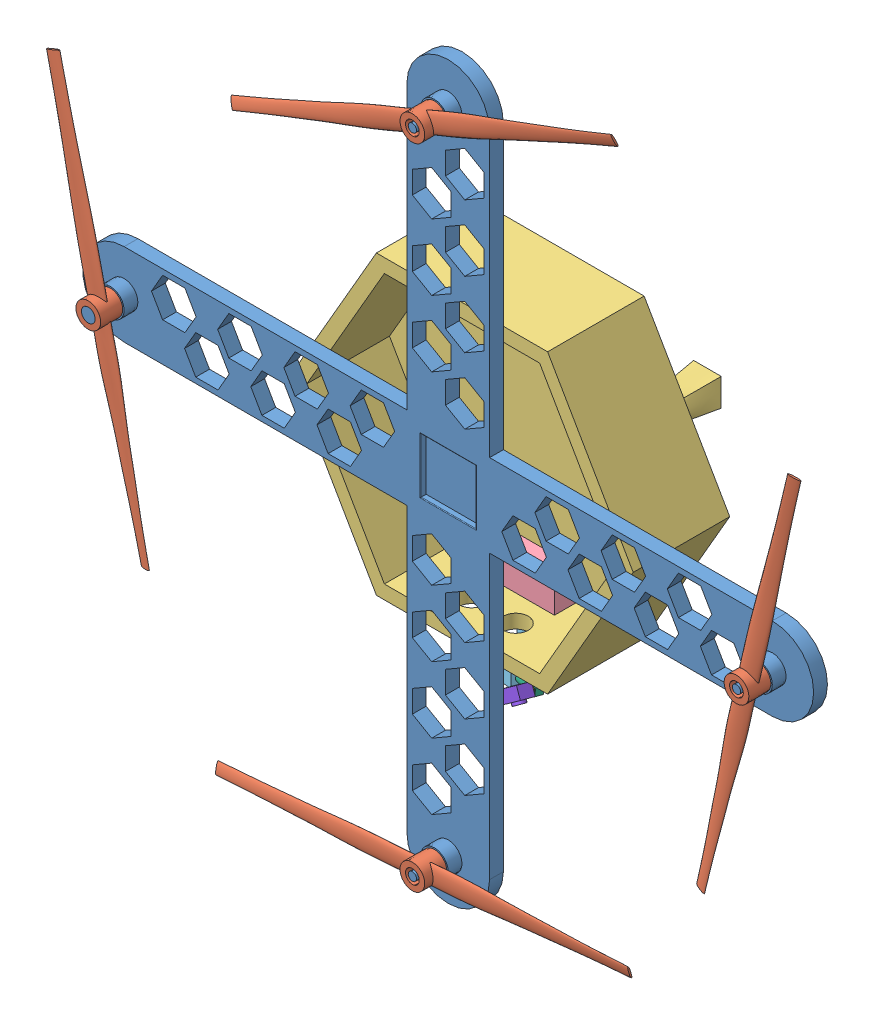
SolidWorks assembly Assembly1, configuration Default. Lengths in mm.
Overall size (277.47 282.88 68.01).
11 component instances, 8 part files, 24 mates.
Components (placement in the parent):
- arm-1: arm [Default] at (-17.0766 -45.3061 35) size (265 265 18)
- blade-1: blade [Default] at (-134.5766 -45.3061 53) x (0.974834 0.222931 0) z (0 0 -1) size (9 150.02 8)
- blade-2: blade [Default] at (-17.0766 72.1939 53) x (0.382949 -0.923769 0) z (0 0 -1) size (9 150.02 8)
- blade-3: blade [Default] at (100.4234 -45.3061 53) x (0.974033 -0.226406 0) z (0 0 -1) size (9 150.02 8)
- blade-4: blade [Default] at (-17.0766 -162.8061 45) x (-0.070402 0.997519 0) z (0 0 1) size (9 150.02 8)
- body-1: body [Default] at (-17.0766 -45.3061 35) x (1 0 0) z (0 0 -1) size (124.13 107.5 50.01)
- gimbal1-1: gimbal1 [Default] at (-17.0766 -84.0561 9.5) x (1 0 0) z (0 -1 0) size (25 9 20)
- gimbal2-1: gimbal2 [Default] at (-17.0766 -99.0561 9.5) x (-0.994374 0 -0.105926) z (0 -1 0) size (15.1 8.17 28)
- gimbal3-1: gimbal3 [Default] at (-22.0484 -124.5561 8.9704) x (-0.104139 0.182919 0.977597) z (0.994374 0 0.105926) size (4 3.01 8)
- gimbal4-1: gimbal4 [Default] at (-15.7412 -124.2817 11.1253) x (0.817116 0.5761 -0.020751) z (-0.104139 0.182919 0.977597) size (2.5 2.5 2.5)
- camera-1: camera [Default] at (-16.0016 -123.8244 13.5693) x (0.817116 0.5761 -0.020751) z (-0.104139 0.182919 0.977597) size (8 5 5)
Mates (geometry in assembly coordinates):
- Concentric1: concentric anti-aligned: cylinder of arm-1 through (-134.5766 -45.3061 53) axis (0 0 -1) radius 2.5; cylinder of blade-1 through (-134.5766 -45.3061 45) axis (0 0 1) radius 2.5
- Coincident3: coincident anti-aligned: plane of arm-1 through (-134.5766 -45.3061 45) normal (0 0 1); plane of blade-1 through (-134.5766 -45.3061 45) normal (0 0 -1)
- Concentric2: concentric aligned: cylinder of arm-1 through (-17.0766 -162.8061 53) axis (0 0 -1) radius 1.5; cylinder of blade-4 through (-17.0766 -162.8061 53) axis (0 0 -1) radius 2.5
- Coincident4: coincident anti-aligned: plane of arm-1 through (-17.0766 -162.8061 45) normal (0 0 1); plane of blade-4 through (-17.0766 -162.8061 45) normal (0 0 -1)
- Concentric3: concentric anti-aligned: cylinder of arm-1 through (100.4234 -45.3061 53) axis (0 0 -1) radius 1.5; cylinder of blade-3 through (100.4234 -45.3061 45) axis (0 0 1) radius 2.5
- Coincident5: coincident anti-aligned: plane of arm-1 through (100.4234 -45.3061 45) normal (0 0 1); plane of blade-3 through (100.4234 -45.3061 45) normal (0 0 -1)
- Concentric5: concentric anti-aligned: cylinder of arm-1 through (-17.0766 72.1939 53) axis (0 0 -1) radius 1.5; cylinder of blade-2 through (-17.0766 72.1939 45) axis (0 0 1) radius 2.5
- Coincident6: coincident anti-aligned: plane of arm-1 through (-17.0766 72.1939 45) normal (0 0 1); plane of blade-2 through (-17.0766 72.1939 45) normal (0 0 -1)
- Coincident7: coincident: point of arm-1; point of body-1
- Parallel4: parallel aligned: plane of arm-1 through (-17.0766 -162.8061 40) normal (0 0 1); plane of body-1 through (-17.0766 -45.3061 5) normal (0 0 1)
- Parallel6: parallel anti-aligned: line of arm-1 through (-32.0766 -162.8061 35) axis (1 0 0); line of body-1 through (13.956 -99.0561 35) axis (-1 0 0)
- Coincident8: coincident anti-aligned: plane of body-1 through (-17.0766 -45.3061 0) normal (0 0 -1)
- Concentric6: concentric anti-aligned: cylinder of body-1 through (-17.0766 8.4449 9.5) axis (0 -1 0) radius 2; cylinder of gimbal1-1 through (-17.0766 -104.0561 9.5) axis (0 1 0) radius 2
- Coincident9: coincident anti-aligned: plane of body-1 through (13.956 -94.0561 0) normal (0 1 0); plane of gimbal1-1 through (-17.0766 -94.0561 9.5) normal (0 -1 0)
- Parallel7: parallel anti-aligned: plane of body-1 through (-17.0766 -45.3061 5) normal (0 0 1); plane of gimbal1-1 through (-29.5766 -94.0561 5) normal (0 0 -1)
- Concentric8: concentric aligned: cylinder of gimbal1-1 through (-17.0766 -104.0561 9.5) axis (0 1 0) radius 2; cylinder of gimbal2-1 through (-17.0766 -104.0561 9.5) axis (0 1 0) radius 2
- Coincident12: coincident anti-aligned: plane of body-1 through (13.956 -99.0561 0) normal (0 -1 0); plane of gimbal2-1 through (-17.0766 -99.0561 9.5) normal (0 1 0)
- Coincident15: coincident anti-aligned: plane of gimbal2-1 through (-22.0484 -99.0561 8.9704) normal (0.994374 0 0.105926); plane of gimbal3-1 through (-22.0484 -124.5561 8.9704) normal (-0.994374 0 -0.105926)
- Concentric11: concentric aligned: cylinder of gimbal2-1 through (-19.0653 -124.5561 9.2881) axis (-0.994374 0 -0.105926) radius 0.75; cylinder of gimbal3-1 through (-19.0653 -124.5561 9.2881) axis (-0.994374 0 -0.105926) radius 0.75
- Concentric12: concentric aligned: cylinder of gimbal3-1 through (-15.8453 -124.0988 12.1029) axis (0.104139 -0.182919 -0.977597) radius 0.75; cylinder of gimbal4-1 through (-15.8453 -124.0988 12.1029) axis (0.104139 -0.182919 -0.977597) radius 0.5
- Coincident16: coincident anti-aligned: plane of gimbal3-1 through (-14.2787 -125.7564 11.557) normal (-0.104139 0.182919 0.977597); plane of gimbal4-1 through (-15.7412 -124.2817 11.1253) normal (0.104139 -0.182919 -0.977597)
- Coincident30: coincident anti-aligned: plane of gimbal4-1 through (-16.0016 -123.8244 13.5693) normal (-0.104139 0.182919 0.977597); plane of camera-1 through (-16.0016 -123.8244 13.5693) normal (0.104139 -0.182919 -0.977597)
- Coincident31: coincident aligned: line of gimbal4-1 through (-15.2928 -124.8202 13.8311) axis (-0.566989 0.796649 -0.209461); line of camera-1 through (-14.8676 -125.4177 13.9882) axis (-0.566989 0.796649 -0.209461)
- Coincident32: coincident anti-aligned: line of gimbal4-1 through (-17.0229 -124.5445 13.5952) axis (0.817116 0.5761 -0.020751); line of camera-1 through (-12.7331 -121.52 13.4863) axis (-0.817116 -0.5761 0.020751)
